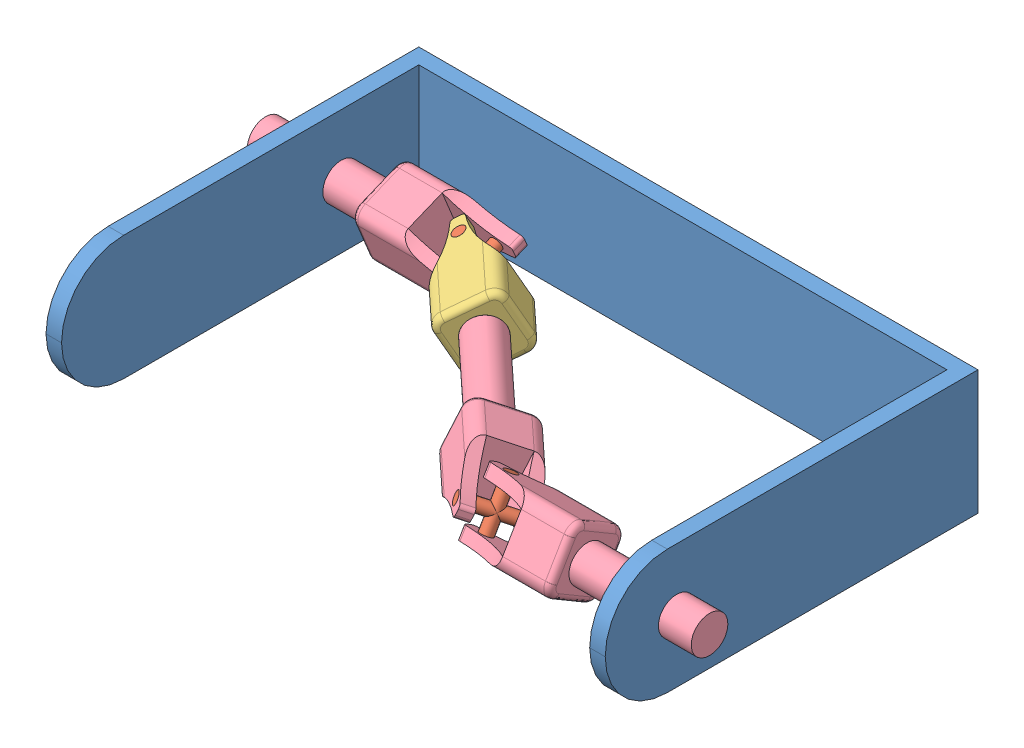
SolidWorks assembly Assem1, configuration Default. Lengths in mm.
Overall size (533.15 101.6 304.8).
7 component instances, 4 part files, 22 mates.
Components (placement in the parent):
- assem 11 part 4-1: assem 11 part 4 [Default] at (-127.8752 125.1875 585.5186) size (457.2 101.6 304.8)
- assem 11 part 2-1: assem 11 part 2 [Default] at (165.5673 185.8941 848.6961) x (-0.780684 -0.317203 -0.538437) z (0.624926 -0.396264 -0.672638) size (10 50 50)
- assem 11 part 3-1: assem 11 part 3 [Default] at (52.9833 175.9875 712.7671) x (0.593746 0.488923 -0.639078) z (-0.732612 0 -0.680646) size (50 50 89.61)
- assembly11 part1-1: assembly11 part1 [Default] at (52.9833 175.9875 712.7671) x (0.269715 0.918137 -0.290308) z (0.732612 0 0.680646) size (50 50 189.61)
- assembly11 part1-2: assembly11 part1 [Default] at (356.1905 175.9875 831.8801) x (0 0.507586 0.861601) z (-1 0 0) size (50 50 189.61)
- assem 11 part 2-2: assem 11 part 2 [Default] at (-10.2822 197.7957 670.6734) x (0.943003 0.307842 0.126405) z (0.332783 -0.872327 -0.358191) size (10 50 50)
- assembly11 part1-5: assembly11 part1 [Default] at (-176.9627 175.9875 661.7186) x (0 0.925052 0.379841) z (1 0 0) size (50 50 189.61)
Mates (geometry in assembly coordinates):
- Concentric1: concentric aligned: cylinder of assem 11 part 4-1 through (-127.8762 175.9875 831.8801) axis (1 0 0) radius 14.985; cylinder of assembly11 part1-2 through (216.1905 175.9875 831.8801) axis (1 0 0) radius 15
- Concentric3: concentric aligned: cylinder of assem 11 part 2-1 through (181.1905 154.4475 844.5698) axis (0 0.861601 -0.507586) radius 5; cylinder of assembly11 part1-2 through (181.1905 154.4475 844.5698) axis (0 0.861601 -0.507586) radius 5
- Coincident1: coincident aligned: plane of assem 11 part 2-1 through (181.1905 154.4475 844.5698) normal (0 -0.861601 0.507586); plane of assembly11 part1-2 through (166.5805 141.7579 823.0297) normal (0 -0.861601 0.507586)
- Concentric4: concentric aligned: cylinder of assem 11 part 2-1 through (196.8136 166.0809 815.0642) axis (-0.624926 0.396264 0.672638) radius 5; cylinder of assembly11 part1-1 through (196.8136 166.0809 815.0642) axis (-0.624926 0.396264 0.672638) radius 5
- Concentric5: concentric aligned: cylinder of assem 11 part 2-1 through (196.8136 166.0809 815.0642) axis (-0.624926 0.396264 0.672638) radius 5; cylinder of assembly11 part1-1 through (196.8136 166.0809 815.0642) axis (-0.624926 0.396264 0.672638) radius 5
- Coincident3: coincident aligned: plane of assem 11 part 2-1 through (165.5673 185.8941 848.6961) normal (-0.624926 0.396264 0.672638); plane of assembly11 part1-1 through (169.5279 162.9407 865.898) normal (-0.624926 0.396264 0.672638)
- Concentric6: concentric aligned: cylinder of assem 11 part 4-1 through (329.3258 175.9875 661.7186) axis (-1 0 0) radius 14.985; cylinder of ? through (-24.6449 175.9875 661.7186) axis (-1 0 0) radius 15
- Concentric7: concentric: cylinder of ? through (10.3551 174.7761 686.6893) axis (0 0.048457 -0.998825) radius 5; cylinder of assem 11 part 2-2 through (10.3551 123.6234 709.237) axis (0 0.998825 0.048457) radius 5
- Coincident6: coincident: plane of ? through (24.9651 199.7467 687.9007) normal (0 -0.048457 0.998825); plane of assem 11 part 2-2
- Coincident7: coincident: plane of ? through (24.9651 199.7467 687.9007) normal (0 -0.048457 0.998825); plane of assem 11 part 2-2
- Concentric8: concentric anti-aligned: cylinder of assem 11 part 4-1 through (329.3258 175.9875 661.7186) axis (-1 0 0) radius 14.985; cylinder of ? through (-428.6572 175.9875 661.7186) axis (1 0 0) radius 15
- Concentric9: concentric aligned: circle of assem 11 part 4-1; cylinder of assembly11 part1-5 through (-36.9627 175.9875 661.7186) axis (-1 0 0) radius 15
- Coincident8: coincident anti-aligned: cylinder of assem 11 part 2-2 through (-1.9627 185.4835 638.5923) axis (0 -0.379841 0.925052) radius 5; circle of assembly11 part1-5
- Coincident9: coincident aligned: cylinder of assem 11 part 2-2 through (-1.9627 185.4835 638.5923) axis (0 -0.379841 0.925052) radius 5; circle of assembly11 part1-5
- Coincident11: coincident aligned: plane of assem 11 part 2-2 through (-1.9627 166.4915 684.8449) normal (0 -0.379841 0.925052); plane of assembly11 part1-5 through (12.6473 143.3652 675.3489) normal (0 -0.379841 0.925052)
- Coincident12: coincident anti-aligned: plane of assem 11 part 3-1 through (52.9833 175.9875 712.7671) normal (0.732612 0 0.680646); plane of assembly11 part1-1 through (52.9833 175.9875 712.7671) normal (-0.732612 0 -0.680646)
- Parallel1: parallel anti-aligned: cylinder of assem 11 part 3-1 through (-10.2822 197.7957 670.6734) axis (0.332783 -0.872327 -0.358191) radius 5; cylinder of assem 11 part 2-2 through (6.3569 154.1794 652.7639) axis (-0.332783 0.872327 0.358191) radius 5
- Parallel2: parallel anti-aligned: cylinder of assem 11 part 3-1 through (-10.2822 197.7957 670.6734) axis (0.332783 -0.872327 -0.358191) radius 5; cylinder of assem 11 part 2-2 through (6.3569 154.1794 652.7639) axis (-0.332783 0.872327 0.358191) radius 5
- Coincident14: coincident aligned: plane of assem 11 part 3-1 through (-35.8294 185.5726 676.7061) normal (-0.332783 0.872327 0.358191); plane of assem 11 part 2-2 through (-10.2822 197.7957 670.6734) normal (-0.332783 0.872327 0.358191)
- Coincident15: coincident aligned: plane of assem 11 part 3-1 through (-19.1902 141.9563 658.7966) normal (0.332783 -0.872327 -0.358191); plane of assem 11 part 2-2 through (6.3569 154.1794 652.7639) normal (0.332783 -0.872327 -0.358191)
- Concentric12: concentric anti-aligned: cylinder of assem 11 part 3-1 through (-10.2822 197.7957 670.6734) axis (0.332783 -0.872327 -0.358191) radius 5; cylinder of assem 11 part 2-2 through (6.3569 154.1794 652.7639) axis (-0.332783 0.872327 0.358191) radius 5
- Concentric13: concentric anti-aligned: cylinder of assem 11 part 3-1 through (-12.6661 175.9875 651.7744) axis (0.732612 0 0.680646) radius 15; cylinder of assembly11 part1-1 through (155.549 175.9875 808.0575) axis (-0.732612 0 -0.680646) radius 15
